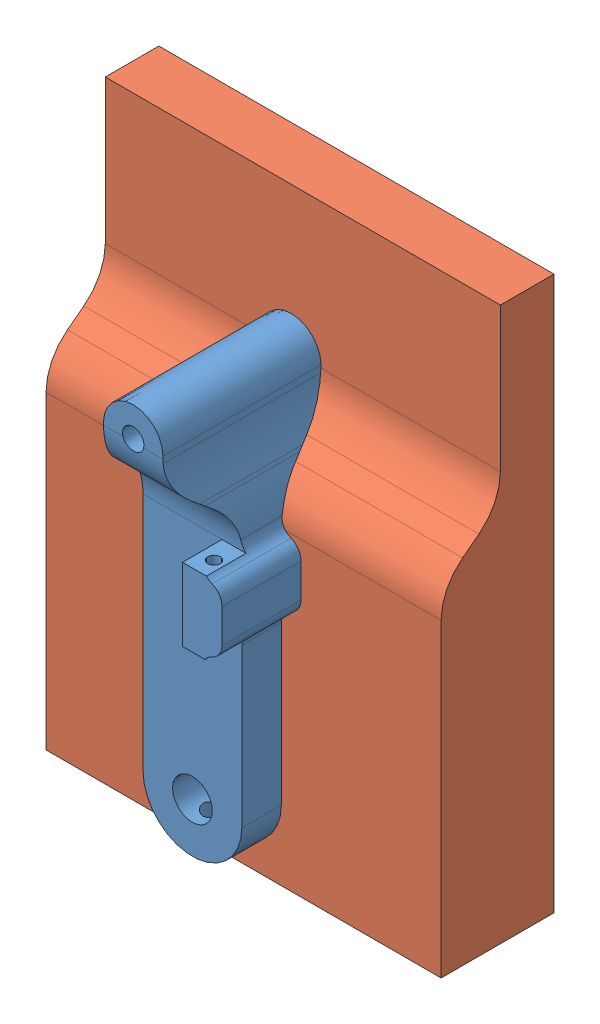
SolidWorks assembly Assem1, configuration Default. Lengths in mm.
Overall size (63.5 88.9 34.01).
2 component instances, 2 part files, 5 mates.
Components (placement in the parent):
- lower_armR3-1: lower_armR3 [Default] at (-60.4548 36.1678 8.6137) size (19.05 67.64 25.4)
- Part1-1: Part1 [Default] at origin size (63.5 88.9 18.14)
Mates (geometry in assembly coordinates):
- InPlace1: in place: plane of Part1-1 through (0 0 0) normal (0 0 1); moOrthogonalPlaneRef_w of Part1-1 through (0 0 0) normal (0 1 0); plane of Part1-1 through (0 0 0) normal (1 0 0); unknown of Part1-1
- Coincident1: coincident aligned: plane of Part1-1; plane of assembly
- Coincident2: coincident aligned: plane of Part1-1 through (0 0 0) normal (0 1 0); moOrthogonalPlaneRef_w of assembly
- Coincident3: coincident anti-aligned: plane of Part1-1 through (0 0 0) normal (1 0 0); moOrthogonalPlaneRef_w of assembly
- Coincident1: coincident anti-aligned: plane of lower_armR3-1 through (-88.7149 36.1678 18.1387) normal (0 0 -1); plane of Part1-1 through (-88.7149 36.1678 18.1387) normal (0 0 1)
